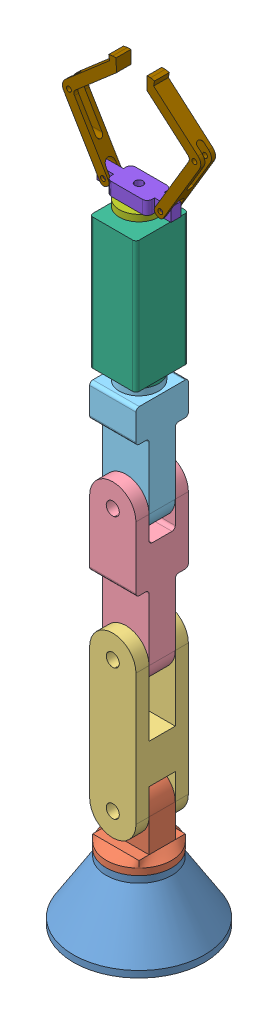
SolidWorks assembly assembly, configuration Default. Lengths in mm.
Overall size (213.5 1139.46 200).
10 component instances, 9 part files, 24 mates.
Components (placement in the parent):
- link_0-1: link_0 [Default] at origin size (200 100 200)
- link_1_x-1: link_1_x [Default] at (0 100 0) x (1 0 0) z (0 1 0) size (100.02 100.02 105.36)
- link_2-1: link_2 [Default] at (0 100 0) x (1 0 0) z (0 0 -1) size (70.71 270.71 80)
- link_3-1: link_3 [Default] at origin size (70.71 270.71 80)
- link_4-1: link_4 [Default] at origin size (70.71 195.36 80)
- link_5-1: link_5 [Default] at (0 730 0) x (1 0 0) z (0 1 0) size (70.71 80 210)
- link_6-1: link_6 [Default] at (0 940 0) x (1 0 0) z (0 1 0) size (60 60 170)
- Bush-1: Bush [Default] at (0 980 0) x (-1 0 0) z (0 -1 0) size (112.5 37.5 20)
- Gripper Arm-1: Gripper Arm [Default] at (63.8146 1049.4708 11.25) x (0 0 -1) z (0.015383 0.999882 0) size (22.5 83.13 178.72)
- Gripper Arm-2: Gripper Arm [Default] at (-63.8146 1049.4708 -11.25) x (0 0 1) z (-0.015383 0.999882 0) size (22.5 83.13 178.72)
Mates (geometry in assembly coordinates):
- InPlace4: in place: plane of ? through (0 0 0) normal (0 0 1); moOrthogonalPlaneRef_w of ? through (0 0 0) normal (0 1 0); plane of ? through (0 0 0) normal (1 0 0); unknown of ?
- Coincident10: coincident aligned: 
- Coincident11: coincident aligned: plane of link_3-1 through (0 0 0) normal (0 1 0)
- Coincident12: coincident anti-aligned: plane of link_3-1 through (0 0 0) normal (1 0 0)
- InPlace5: in place: plane of ? through (0 0 0) normal (0 0 1); plane of ? through (0 0 0) normal (0 1 0); plane of ? through (0 0 0) normal (1 0 0); unknown of ?
- Coincident13: coincident aligned: 
- Coincident14: coincident aligned: plane of link_4-1 through (0 0 0) normal (0 1 0)
- Coincident15: coincident anti-aligned: plane of link_4-1 through (0 0 0) normal (1 0 0)
- InPlace6: in place: plane of ? through (0 780 0) normal (0 1 0); plane of ? through (0 780 0) normal (0 1 0); plane of ? through (0 780 0) normal (0 1 0); plane of ? through (0 780 0) normal (0 0 -1); plane of ? through (0 780 0) normal (0 1 0); plane of ? through (0 780 0) normal (1 0 0); plane of ? through (0 730 0) normal (0 1 0); unknown of link_5-1
- Coincident1: coincident aligned: plane of link_4-1; plane of link_5-1
- Coincident2: coincident aligned: moOrthogonalPlaneRef_w of link_4-1 through (0 730 0) normal (0 0 -1); plane of link_5-1 through (0 730 0) normal (0 0 -1)
- Coincident3: coincident anti-aligned: moOrthogonalPlaneRef_w of link_4-1 through (0 730 0) normal (-1 0 0); plane of link_5-1 through (0 730 0) normal (1 0 0)
- InPlace7: in place: plane of link_5-1 through (0 940 0) normal (0 1 0); plane of link_6-1 through (0 940 0) normal (0 1 0); plane of link_5-1 through (0 940 0) normal (0 1 0); plane of link_6-1 through (0 940 0) normal (0 0 -1); plane of link_5-1 through (0 940 0) normal (0 1 0); plane of link_6-1 through (0 940 0) normal (1 0 0); plane of link_5-1 through (0 940 0) normal (0 1 0); unknown of link_6-1
- Coincident1: coincident aligned: plane of link_5-1; plane of link_6-1
- Coincident2: coincident aligned: moOrthogonalPlaneRef_w of link_5-1 through (0 940 0) normal (0 0 -1); plane of link_6-1 through (0 940 0) normal (0 0 -1)
- Coincident3: coincident anti-aligned: moOrthogonalPlaneRef_w of link_5-1 through (0 940 0) normal (-1 0 0); plane of link_6-1 through (0 940 0) normal (1 0 0)
- Concentric1: concentric anti-aligned: circle of link_6-1; circle of Bush-1
- Coincident1: coincident anti-aligned: plane of link_6-1 through (0 960 0) normal (0 1 0); plane of Bush-1 through (0 960 0) normal (0 -1 0)
- Parallel1: parallel aligned: plane of link_5-1 through (35.3553 940 40) normal (0 0 1); plane of Bush-1 through (0 960 18.75) normal (0 0 1)
- Concentric2: concentric aligned: cylinder of Bush-1 through (43.75 970 12.5) axis (0 0 -1) radius 4.375; cylinder of Gripper Arm-1 through (43.75 970 488.75) axis (0 0 -1) radius 3.75
- Coincident2: coincident anti-aligned: plane of Bush-1 through (0 960 7.5) normal (0 0 1); plane of Gripper Arm-1 through (312.8844 987.0846 7.5) normal (0 0 -1)
- Concentric3: concentric anti-aligned: cylinder of Bush-1 through (-43.75 970 12.5) axis (0 0 -1) radius 4.375; cylinder of Gripper Arm-2 through (-43.75 970 -488.75) axis (0 0 1) radius 3.75
- Coincident3: coincident anti-aligned: plane of Bush-1 through (0 960 7.5) normal (0 0 1); plane of Gripper Arm-2 through (-312.8844 987.0846 7.5) normal (0 0 -1)
- Symmetric1: symmetric aligned: plane of Gripper Arm-1 through (23.6274 1139.4575 11.25) normal (-0.999882 0.015383 0); plane of Gripper Arm-2 through (-23.6274 1139.4575 -11.25) normal (0.999882 0.015383 0)
